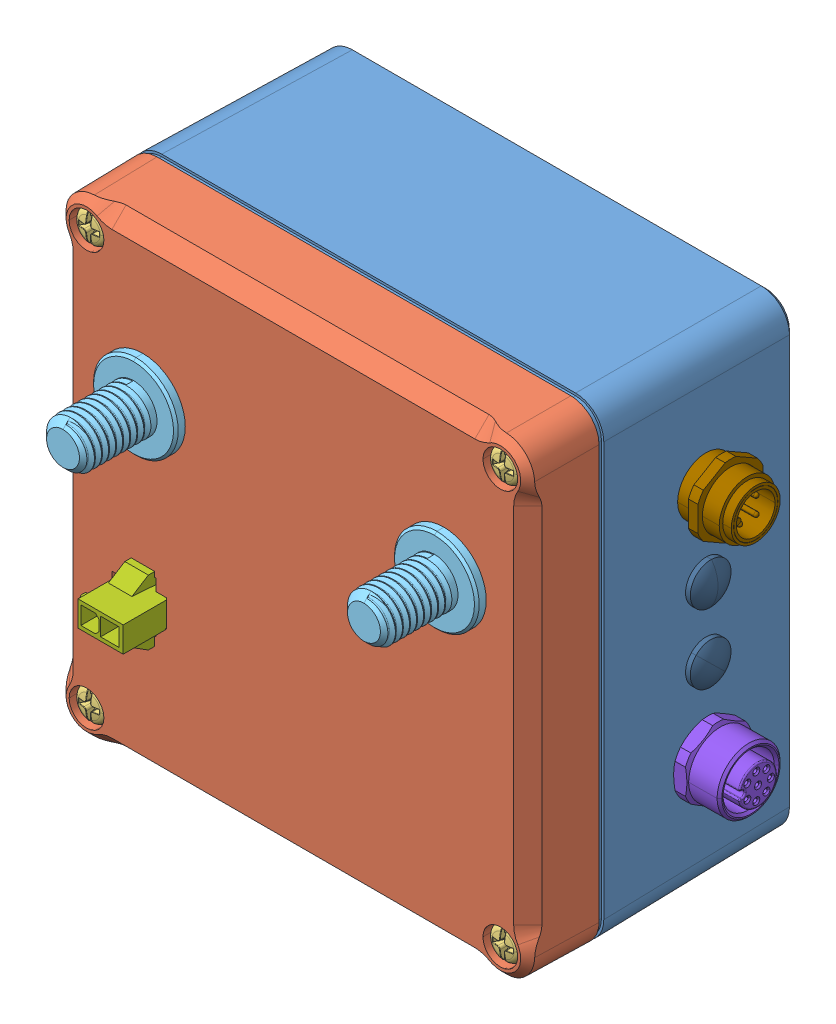
SolidWorks assembly PUTM-H-TS-BOX-data_logger, configuration Domyślna. Lengths in mm.
Overall size (111.68 104.32 74.5).
17 component instances, 10 part files, 0 mates.
Components (placement in the parent):
- PUTM-H-TS-EB-data_logger.STEP-1: PUTM-H-TS-EB-data_logger.STEP [Domyślna] at origin size (111.68 104.32 74.5)
  - 63212000_ET_212.STEP-1: 63212000_ET_212.STEP [Domyślna] x (-1 0 0) z (0 0 1) size (101.62 104.32 57.5)
    - 212 UT_1002700_3DSYM.STEP-1: 212 UT_1002700_3DSYM.STEP [Domyślna] at origin size (100.01 100.01 44.01)
    - 212 OT_1002699_3DSYM.STEP-1: 212 OT_1002699_3DSYM.STEP [Domyślna] at (-10 50 19) x (1 0 0) z (0 0 -1) size (101.62 101.62 15)
    - SHR Z KAL40X25X10 WN 1412 MG_3DSYM.STEP-1: SHR Z KAL40X25X10 WN 1412 MG_3DSYM.STEP [Domyślna] at (-54 6 24.85) size (7.01 7.01 28.04)
    - SHR Z KAL40X25X10 WN 1412 MG_3DSYM.STEP-2: SHR Z KAL40X25X10 WN 1412 MG_3DSYM.STEP [Domyślna] at (-54 94 24.85) size (7.01 7.01 28.04)
    - SHR Z KAL40X25X10 WN 1412 MG_3DSYM.STEP-3: SHR Z KAL40X25X10 WN 1412 MG_3DSYM.STEP [Domyślna] at (34 6 24.85) size (7.01 7.01 28.04)
    - SHR Z KAL40X25X10 WN 1412 MG_3DSYM.STEP-4: SHR Z KAL40X25X10 WN 1412 MG_3DSYM.STEP [Domyślna] at (34 94 24.85) size (7.01 7.01 28.04)
  - IVTModul.STEP-1: IVTModul.STEP [Domyślna] at (10 -31.7 14) x (-1 0 0) z (0 -1 0) size (84 24.2 85.3)
  - Kupferkontakt.STEP-1: Kupferkontakt.STEP [Domyślna] at (-22 -31.7 43.5) x (-1 0 0) z (0 1 0) size (18 27.8 18)
  - Kupferkontakt.STEP-2: Kupferkontakt.STEP [Domyślna] at (42 -31.7 43.5) x (-1 0 0) z (0 1 0) size (18 27.8 18)
  - GFK-Verdrehschutz.STEP-1: GFK-Verdrehschutz.STEP [Domyślna] at (10 -31.7 23.5) x (-1 0 0) z (0 -1 0) size (84 8 20)
  - Molex Stecker.STEP-1: Molex Stecker.STEP [Domyślna] at (-16.2 -68.4996 35.5) x (0 1 0) z (0 0 1) size (13.8 12 23.9)
  - Stecker 8 pol.STEP-1: Stecker 8 pol.STEP [Domyślna] at (52.8003 -74.85 -11.3612) x (0.999962 0 -0.008727) z (0.008727 0 0.999962) size (27.22 19.53 19.87)
  - Stecker 4 pol.STEP-1: Stecker 4 pol.STEP [Domyślna] at (54.8003 -25.15 -11.3787) x (0 1 0) z (0.008727 0 0.999962) size (20 25.54 21.7)
  - LED.STEP-1: LED.STEP [Domyślna] at (51.4204 -57.35 -11.3492) x (-0.00624 -0.699028 -0.715067) z (-0.999962 0 0.008727) size (8.74 8.74 10.92)
  - LED.STEP-2: LED.STEP [Domyślna] at (51.4204 -42.65 -11.3492) x (-0.000345 0.99922 -0.039489) z (-0.999962 0 0.008727) size (8.74 8.74 10.92)
